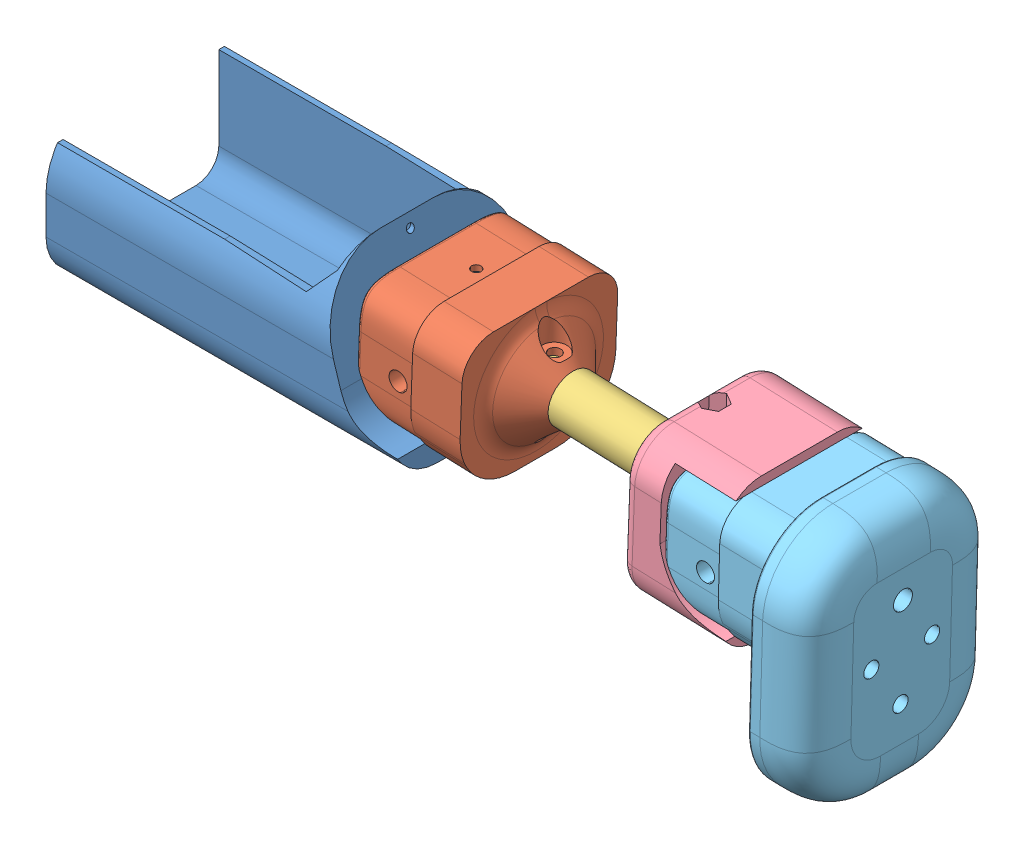
SolidWorks assembly Ensamblaje1, configuration Predeterminado. Lengths in mm.
Overall size (201.27 68.53 50.1).
5 component instances, 5 part files, 10 mates.
Components (placement in the parent):
- pinon Dispensador.STL-1: pinon Dispensador.STL [Predeterminado] at origin size (99.22 48 50)
- union superior-1: union superior [Predeterminado] at (35.2167 0.4343 0) x (0.999294 -0.037582 0) z (0 0 1) size (37.05 36 41.81)
- Tubo-1: Tubo [Predeterminado] at (76.1877 -1.1066 0) x (-0.036641 -0.974252 0.222466) z (-0.999294 0.037582 0) size (12.5 12.5 50)
- union inferior-1: union inferior [Predeterminado] at (116.1761 -2.6105 0) x (0.037582 0.999294 0) z (0 0 1) size (38.5 37.02 40)
- pie-1: pie [Predeterminado] at (116.1761 -2.6105 0) x (0.999621 -0.027541 0) z (0 0 1) size (43.1 65.1 50.1)
Mates (geometry in assembly coordinates):
- Coincidente1: coordinate: point of pinon Dispensador.STL-1
- Concéntrica1: concentric anti-aligned: cylinder of pinon Dispensador.STL-1 through (35.2167 0.4343 5) axis (0 0 -1) radius 2.5; cylinder of union superior-1 through (35.2167 0.4343 -35.75) axis (0 0 1) radius 2.3813
- Coincidente2: coincident aligned: plane of pinon Dispensador.STL-1 through (0 0 0) normal (0 0 1); plane of union superior-1 through (35.2167 0.4343 0) normal (0 0 1)
- Coincidente3: coincident anti-aligned: plane of union superior-1 through (51.2054 -0.167 0) normal (0.999294 -0.037582 0); plane of Tubo-1 through (51.2054 -0.167 0) normal (-0.999294 0.037582 0)
- Concéntrica2: concentric anti-aligned: cylinder of union superior-1 through (35.2167 0.4343 0) axis (-0.999294 0.037582 0) radius 6; cylinder of Tubo-1 through (51.2054 -0.167 0) axis (0.999294 -0.037582 0) radius 6.25
- Concéntrica3: concentric anti-aligned: cylinder of Tubo-1 through (51.2054 -0.167 0) axis (0.999294 -0.037582 0) radius 6.25; cylinder of union inferior-1 through (101.17 -2.0461 0) axis (-0.999294 0.037582 0) radius 6.5
- Coincidente4: coincident anti-aligned: plane of Tubo-1 through (101.17 -2.0461 0) normal (0.999294 -0.037582 0); plane of union inferior-1 through (101.17 -2.0461 0) normal (-0.999294 0.037582 0)
- Coincidente5: coincident aligned: plane of union superior-1 through (35.2167 0.4343 0) normal (0 0 1); plane of union inferior-1 through (116.1761 -2.6105 0) normal (0 0 1)
- Concéntrica4: concentric anti-aligned: cylinder of union inferior-1 through (116.1761 -2.6105 4) axis (0 0 -1) radius 2.3813; cylinder of pie-1 through (116.1761 -2.6105 -35.75) axis (0 0 1) radius 2.3813
- Coincidente6: coincident aligned: plane of union superior-1 through (35.2167 0.4343 0) normal (0 0 1); plane of pie-1 through (116.1761 -2.6105 0) normal (0 0 1)
